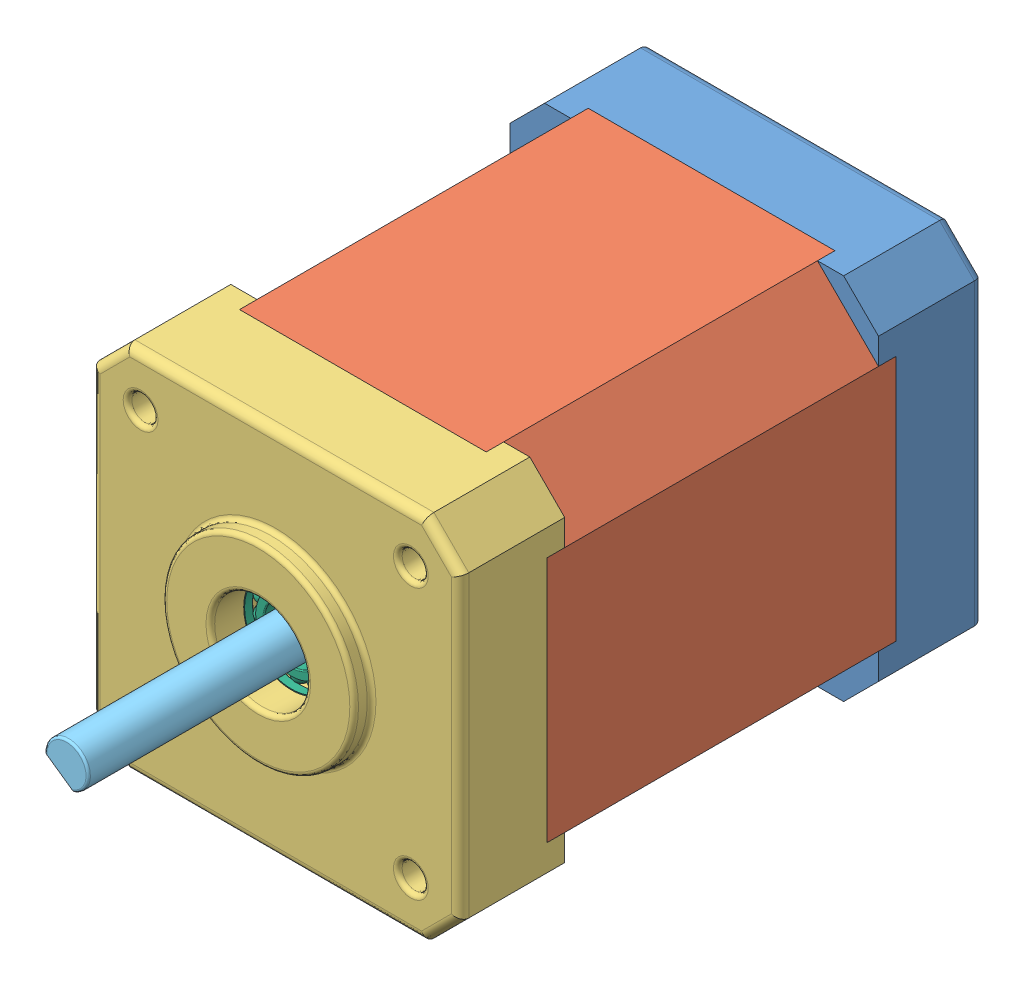
SolidWorks assembly NEMA_17_60mm_1.5A, configuration Predeterminado. Lengths in mm.
Overall size (42.3 42.3 84.16).
10 component instances, 6 part files, 21 mates.
Components (placement in the parent):
- Base-1: Base [Predeterminado] at (-10.3955 4.6172 0) size (42.3 42.3 12)
- Body_60mm-1: Body_60mm [Predeterminado] at (-10.3955 4.6172 10) size (42.3 42.3 40)
- FaceCap-1: FaceCap [Predeterminado] at (-10.3955 4.6172 60) x (-1 0 0) z (0 0 -1) size (42.3 42.3 14)
- 3mmX50mm_Sockethead(McMaster_91290A137)-1: 3mmX50mm_Sockethead(McMaster_91290A137) [91290A137] at (5.1045 20.1172 53) x (-0.078076 -0.996947 0) z (0 0 1) size (5.5 5.5 53.26)
- 3mmX50mm_Sockethead(McMaster_91290A137)-2: 3mmX50mm_Sockethead(McMaster_91290A137) [91290A137] at (-25.8955 20.1172 53) x (0.373638 -0.927575 0) z (0 0 1) size (5.5 5.5 53.26)
- 3mmX50mm_Sockethead(McMaster_91290A137)-3: 3mmX50mm_Sockethead(McMaster_91290A137) [91290A137] at (-25.8955 -10.8828 53) x (-0.535522 -0.844521 0) z (0 0 1) size (5.5 5.5 53.26)
- 3mmX50mm_Sockethead(McMaster_91290A137)-4: 3mmX50mm_Sockethead(McMaster_91290A137) [91290A137] at (5.1045 -10.8828 53) x (-0.438078 -0.898937 0) z (0 0 1) size (5.5 5.5 53.26)
- Shaft_60mm-1: Shaft_60mm [Predeterminado] at (-10.3955 4.6172 0) x (0.574856 0.818255 0) z (0 0 1) size (5 5 84.02)
- instrument ball bearing_68_am-2: instrument ball bearing_68_am [PreviewCfg] at (-10.3955 4.6172 56.5875) x (0 0 -1) z (0.994238 0.107199 0) size (3.17 12.7 12.7)
- instrument ball bearing_68_am-4: instrument ball bearing_68_am [PreviewCfg] at (-10.3955 4.6172 3.4125) x (0 0 1) z (-0.739703 -0.672934 0) size (3.17 12.7 12.7)
Mates (geometry in assembly coordinates):
- Paralelo1: parallel anti-aligned: plane of Base-1 through (-10.3955 4.6172 10) normal (0 0 1); plane of Body_60mm-1 through (-10.3955 4.6172 10) normal (0 0 -1)
- Coincidente2: coincident aligned: plane of Base-1 through (-27.5455 25.7672 12) normal (0 1 0); plane of Body_60mm-1 through (-24.5455 25.7672 50) normal (0 1 0)
- Coincidente3: coincident aligned: plane of Base-1 through (-31.5455 21.7672 12) normal (-1 0 0); plane of Body_60mm-1 through (-31.5455 18.7672 50) normal (-1 0 0)
- Coincidente4: coincident anti-aligned: plane of Base-1 through (-10.3955 4.6172 10) normal (0 0 1); plane of Body_60mm-1 through (-10.3955 4.6172 10) normal (0 0 -1)
- Coincidente5: coincident anti-aligned: plane of Body_60mm-1 through (-10.3955 4.6172 50) normal (0 0 1); plane of FaceCap-1 through (-10.3955 4.6172 50) normal (0 0 -1)
- Coincidente6: coincident aligned: plane of Body_60mm-1 through (-31.5455 18.7672 50) normal (-1 0 0); plane of FaceCap-1 through (-31.5455 21.7672 48) normal (-1 0 0)
- Coincidente7: coincident aligned: plane of Body_60mm-1 through (-24.5455 25.7672 50) normal (0 1 0); plane of FaceCap-1 through (6.7545 25.7672 48) normal (0 1 0)
- Concéntrica5: concentric anti-aligned: cylinder of Base-1 through (5.1045 20.1172 22) axis (0 0 -1) radius 1.5; cylinder of 3mmX50mm_Sockethead(McMaster_91290A137)-1 through (5.1045 20.1172 3) axis (0 0 1) radius 1.5
- Coincidente8: coincident anti-aligned: plane of Base-1 through (5.1045 20.1172 3) normal (0 0 -1); plane of 3mmX50mm_Sockethead(McMaster_91290A137)-1 through (5.1045 20.1172 3) normal (0 0 1)
- Concéntrica6: concentric anti-aligned: cylinder of Base-1 through (-25.8955 20.1172 22) axis (0 0 -1) radius 1.5; cylinder of 3mmX50mm_Sockethead(McMaster_91290A137)-2 through (-25.8955 20.1172 3) axis (0 0 1) radius 1.5
- Concéntrica7: concentric anti-aligned: cylinder of Base-1 through (-25.8955 -10.8828 22) axis (0 0 -1) radius 1.5; cylinder of 3mmX50mm_Sockethead(McMaster_91290A137)-3 through (-25.8955 -10.8828 3) axis (0 0 1) radius 1.5
- Concéntrica8: concentric anti-aligned: cylinder of Base-1 through (5.1045 -10.8828 22) axis (0 0 -1) radius 1.5; cylinder of 3mmX50mm_Sockethead(McMaster_91290A137)-4 through (5.1045 -10.8828 3) axis (0 0 1) radius 1.5
- Coincidente9: coincident anti-aligned: circle of Base-1; plane of 3mmX50mm_Sockethead(McMaster_91290A137)-3 through (-25.8955 -10.8828 3) normal (0 0 1)
- Coincidente10: coincident anti-aligned: plane of Base-1 through (5.1045 -10.8828 3) normal (0 0 -1); plane of 3mmX50mm_Sockethead(McMaster_91290A137)-4 through (5.1045 -10.8828 3) normal (0 0 1)
- Coincidente11: coincident anti-aligned: plane of Base-1 through (-25.8955 20.1172 3) normal (0 0 -1); plane of 3mmX50mm_Sockethead(McMaster_91290A137)-2 through (-25.8955 20.1172 3) normal (0 0 1)
- Concéntrica10: concentric aligned: cylinder of Base-1 through (-10.3955 4.6172 22) axis (0 0 -1) radius 2.5; cylinder of Shaft_60mm-1 through (-10.3955 4.6172 84) axis (0 0 -1) radius 2.5
- Concéntrica14: concentric aligned: cylinder of Shaft_60mm-1 through (-10.3955 4.6172 84) axis (0 0 -1) radius 2.5; cylinder of instrument ball bearing_68_am-2 through (-10.3955 4.6172 77.225) axis (0 0 -1) radius 3.175
- Concéntrica15: concentric anti-aligned: cylinder of Shaft_60mm-1 through (-10.3955 4.6172 84) axis (0 0 -1) radius 2.5; cylinder of instrument ball bearing_68_am-4 through (-10.3955 4.6172 -17.225) axis (0 0 1) radius 6.35
- Coincidente12: coincident aligned: plane of Base-1 through (-10.3955 4.6172 0) normal (0 0 -1); plane of Shaft_60mm-1 through (-10.3955 4.6172 0) normal (0 0 -1)
- Coincident1: coincident anti-aligned: plane of FaceCap-1 through (-10.3955 4.6172 55) normal (0 0 1); plane of instrument ball bearing_68_am-2 through (-11.0626 10.8043 55) normal (0 0 -1)
- Coincident2: coincident anti-aligned: plane of Base-1 through (-10.3955 4.6172 5) normal (0 0 -1); plane of instrument ball bearing_68_am-4 through (-14.5832 9.2203 5) normal (0 0 1)
